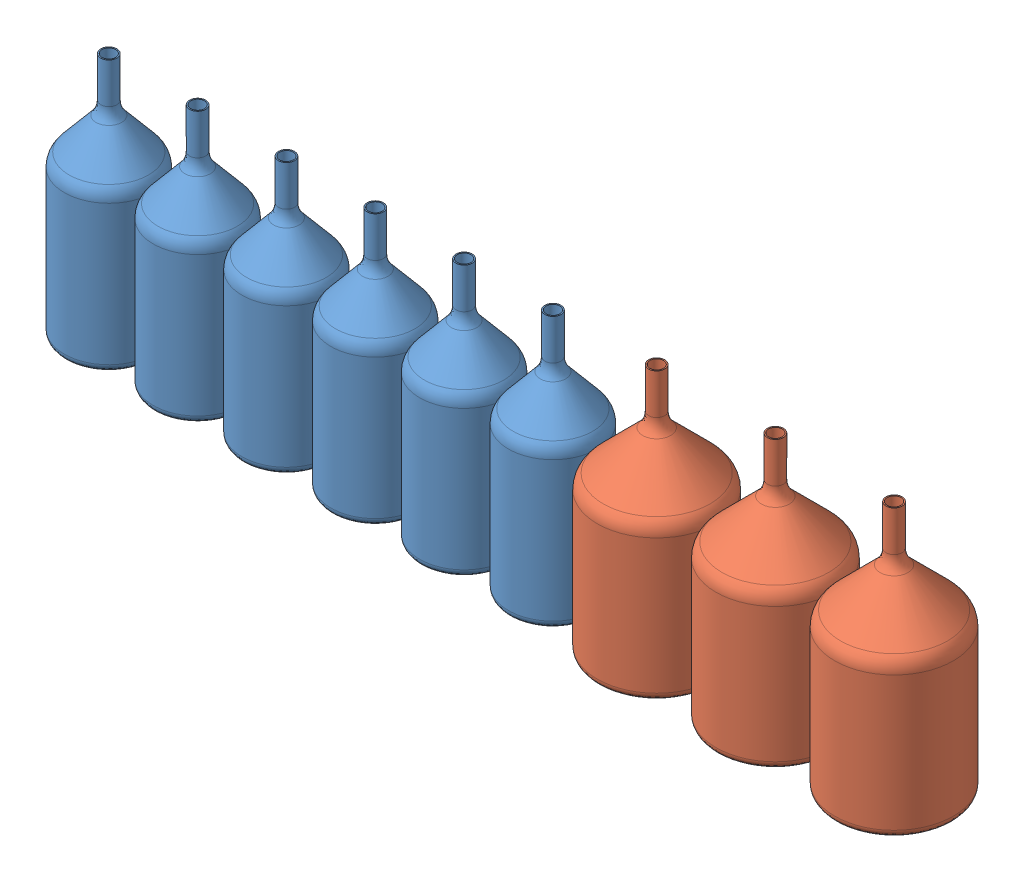
SolidWorks assembly Fit bouteilles, configuration Défaut. Lengths in mm.
Overall size (1101 310.8 147).
9 component instances, 2 part files, 27 mates.
Components (placement in the parent):
- bouteille 110 mm-1: bouteille 110 mm [Défaut] at origin size (110 305 110)
- bouteille 110 mm-2: bouteille 110 mm [Défaut] at (110 0 0) size (110 305 110)
- bouteille 110 mm-3: bouteille 110 mm [Défaut] at (220 0 0) size (110 305 110)
- bouteille 110 mm-4: bouteille 110 mm [Défaut] at (330 0 0) size (110 305 110)
- bouteille 110 mm-5: bouteille 110 mm [Défaut] at (440 0 0) size (110 305 110)
- bouteille 110 mm-6: bouteille 110 mm [Défaut] at (550 0 0) size (110 305 110)
- bouteille 147 mm-1: bouteille 147 mm [Défaut] at (678.5 0 0) size (147 310.8 147)
- bouteille 147 mm-2: bouteille 147 mm [Défaut] at (825.5 0 0) size (147 310.8 147)
- bouteille 147 mm-3: bouteille 147 mm [Défaut] at (972.5 0 0) size (147 310.8 147)
Mates (geometry in assembly coordinates):
- Coïncidente1: coincident aligned: plane of bouteille 110 mm-1 through (0 0 0) normal (0 0 1)
- Coïncidente2: coincident aligned: plane of bouteille 110 mm-1 through (0 0 0) normal (0 1 0)
- Coïncidente3: coincident aligned: plane of bouteille 110 mm-1 through (0 0 0) normal (1 0 0)
- Coïncidente4: coincident aligned: plane of bouteille 110 mm-2 through (110 0 0) normal (0 0 1)
- Coïncidente5: coincident aligned: plane of bouteille 110 mm-2 through (110 0 0) normal (0 1 0)
- Coïncidente6: coincident aligned: plane of bouteille 110 mm-3 through (220 0 0) normal (0 0 1)
- Coïncidente7: coincident aligned: plane of bouteille 110 mm-3 through (220 0 0) normal (0 1 0)
- Coïncidente8: coincident aligned: plane of bouteille 110 mm-4 through (330 0 0) normal (0 0 1)
- Coïncidente9: coincident aligned: plane of bouteille 110 mm-4 through (330 0 0) normal (0 1 0)
- Coïncidente10: coincident aligned: plane of bouteille 110 mm-5 through (440 0 0) normal (0 0 1)
- Coïncidente11: coincident aligned: plane of bouteille 110 mm-5 through (440 0 0) normal (0 1 0)
- Coïncidente12: coincident aligned: plane of bouteille 110 mm-6 through (550 0 0) normal (0 0 1)
- Coïncidente13: coincident aligned: plane of bouteille 110 mm-6 through (550 0 0) normal (0 1 0)
- Tangent1: tangent anti-aligned: cylinder of bouteille 110 mm-1 through (0 0 0) axis (0 -1 0) radius 55; cylinder of bouteille 110 mm-2 through (110 0 0) axis (0 -1 0) radius 55
- Tangent2: tangent anti-aligned: cylinder of bouteille 110 mm-2 through (110 0 0) axis (0 -1 0) radius 55; cylinder of bouteille 110 mm-3 through (220 0 0) axis (0 -1 0) radius 55
- Tangent3: tangent anti-aligned: cylinder of bouteille 110 mm-3 through (220 0 0) axis (0 -1 0) radius 55; cylinder of bouteille 110 mm-4 through (330 0 0) axis (0 -1 0) radius 55
- Tangent4: tangent anti-aligned: cylinder of bouteille 110 mm-4 through (330 0 0) axis (0 -1 0) radius 55; cylinder of bouteille 110 mm-5 through (440 0 0) axis (0 -1 0) radius 55
- Tangent5: tangent anti-aligned: cylinder of bouteille 110 mm-5 through (440 0 0) axis (0 -1 0) radius 55; cylinder of bouteille 110 mm-6 through (550 0 0) axis (0 -1 0) radius 55
- Coïncidente14: coincident aligned: plane of bouteille 147 mm-1 through (678.5 0 0) normal (0 0 1)
- Coïncidente15: coincident aligned: plane of bouteille 147 mm-1 through (678.5 0 0) normal (0 1 0)
- Coïncidente16: coincident aligned: plane of bouteille 147 mm-2 through (825.5 0 0) normal (0 0 1)
- Coïncidente17: coincident aligned: plane of bouteille 147 mm-2 through (825.5 0 0) normal (0 1 0)
- Coïncidente18: coincident aligned: plane of bouteille 147 mm-3 through (972.5 0 0) normal (0 0 1)
- Coïncidente19: coincident aligned: plane of bouteille 147 mm-3 through (972.5 0 0) normal (0 1 0)
- Tangent6: tangent anti-aligned: cylinder of bouteille 110 mm-6 through (550 0 0) axis (0 -1 0) radius 55; cylinder of bouteille 147 mm-1 through (678.5 0 0) axis (0 -1 0) radius 73.5
- Tangent7: tangent anti-aligned: cylinder of bouteille 147 mm-1 through (678.5 0 0) axis (0 -1 0) radius 73.5; cylinder of bouteille 147 mm-2 through (825.5 0 0) axis (0 -1 0) radius 73.5
- Tangent8: tangent anti-aligned: cylinder of bouteille 147 mm-2 through (825.5 0 0) axis (0 -1 0) radius 73.5; cylinder of bouteille 147 mm-3 through (972.5 0 0) axis (0 -1 0) radius 73.5
